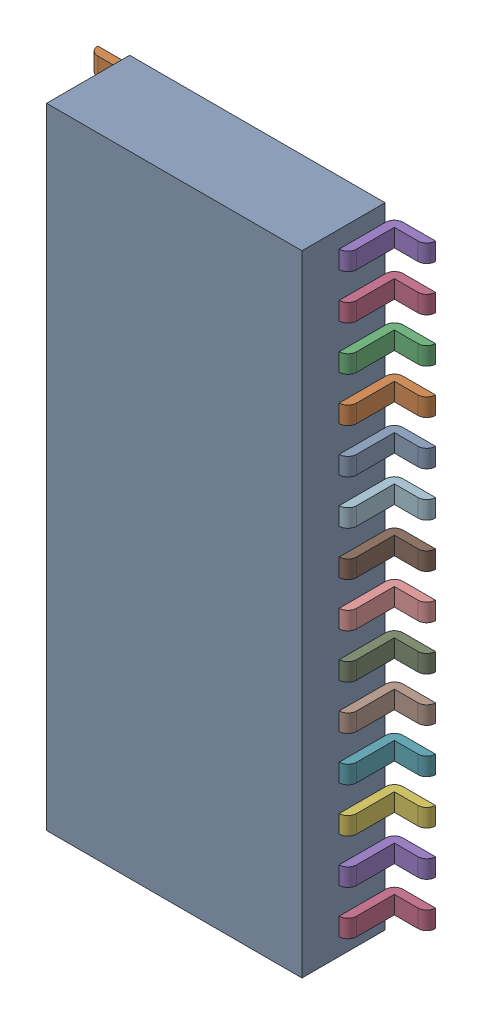
SolidWorks assembly Open CASCADE STEP translator 6.8 1.3.1, configuration Predeterminado. Lengths in mm.
Overall size (9.65 18 2.64).
29 component instances, 29 part files, 0 mates.
Components (placement in the parent):
- Body_1-1: Body_1 [Predeterminado] at origin size (7.3 18 2.38)
- Pin_1-1: Pin_1 [Predeterminado] at origin size (1.17 0.51 1.58)
- Pin_2-1: Pin_2 [Predeterminado] at origin size (1.17 0.51 1.58)
- Pin_3-1: Pin_3 [Predeterminado] at origin size (1.17 0.51 1.58)
- Pin_4-1: Pin_4 [Predeterminado] at origin size (1.17 0.51 1.58)
- Pin_5-1: Pin_5 [Predeterminado] at origin size (1.17 0.51 1.58)
- Pin_6-1: Pin_6 [Predeterminado] at origin size (1.17 0.51 1.58)
- Pin_7-1: Pin_7 [Predeterminado] at origin size (1.17 0.51 1.58)
- Pin_8-1: Pin_8 [Predeterminado] at origin size (1.17 0.51 1.58)
- Pin_9-1: Pin_9 [Predeterminado] at origin size (1.17 0.51 1.58)
- Pin_10-1: Pin_10 [Predeterminado] at origin size (1.17 0.51 1.58)
- Pin_11-1: Pin_11 [Predeterminado] at origin size (1.17 0.51 1.58)
- Pin_12-1: Pin_12 [Predeterminado] at origin size (1.17 0.51 1.58)
- Pin_13-1: Pin_13 [Predeterminado] at origin size (1.17 0.51 1.58)
- Pin_14-1: Pin_14 [Predeterminado] at origin size (1.17 0.51 1.58)
- Pin_15-1: Pin_15 [Predeterminado] at (18.8 -17.78 0) x (-1 0 0) z (0 0 1) size (1.17 0.51 1.58)
- Pin_16-1: Pin_16 [Predeterminado] at (18.8 -15.24 0) x (-1 0 0) z (0 0 1) size (1.17 0.51 1.58)
- Pin_17-1: Pin_17 [Predeterminado] at (18.8 -12.7 0) x (-1 0 0) z (0 0 1) size (1.17 0.51 1.58)
- Pin_18-1: Pin_18 [Predeterminado] at (18.8 -10.16 0) x (-1 0 0) z (0 0 1) size (1.17 0.51 1.58)
- Pin_19-1: Pin_19 [Predeterminado] at (18.8 -7.62 0) x (-1 0 0) z (0 0 1) size (1.17 0.51 1.58)
- Pin_20-1: Pin_20 [Predeterminado] at (18.8 -5.08 0) x (-1 0 0) z (0 0 1) size (1.17 0.51 1.58)
- Pin_21-1: Pin_21 [Predeterminado] at (18.8 -2.54 0) x (-1 0 0) z (0 0 1) size (1.17 0.51 1.58)
- Pin_22-1: Pin_22 [Predeterminado] at (18.8 0 0) x (-1 0 0) z (0 0 1) size (1.17 0.51 1.58)
- Pin_23-1: Pin_23 [Predeterminado] at (18.8 2.54 0) x (-1 0 0) z (0 0 1) size (1.17 0.51 1.58)
- Pin_24-1: Pin_24 [Predeterminado] at (18.8 5.08 0) x (-1 0 0) z (0 0 1) size (1.17 0.51 1.58)
- Pin_25-1: Pin_25 [Predeterminado] at (18.8 7.62 0) x (-1 0 0) z (0 0 1) size (1.17 0.51 1.58)
- Pin_26-1: Pin_26 [Predeterminado] at (18.8 10.16 0) x (-1 0 0) z (0 0 1) size (1.17 0.51 1.58)
- Pin_27-1: Pin_27 [Predeterminado] at (18.8 12.7 0) x (-1 0 0) z (0 0 1) size (1.17 0.51 1.58)
- Pin_28-1: Pin_28 [Predeterminado] at (18.8 15.24 0) x (-1 0 0) z (0 0 1) size (1.17 0.51 1.58)
